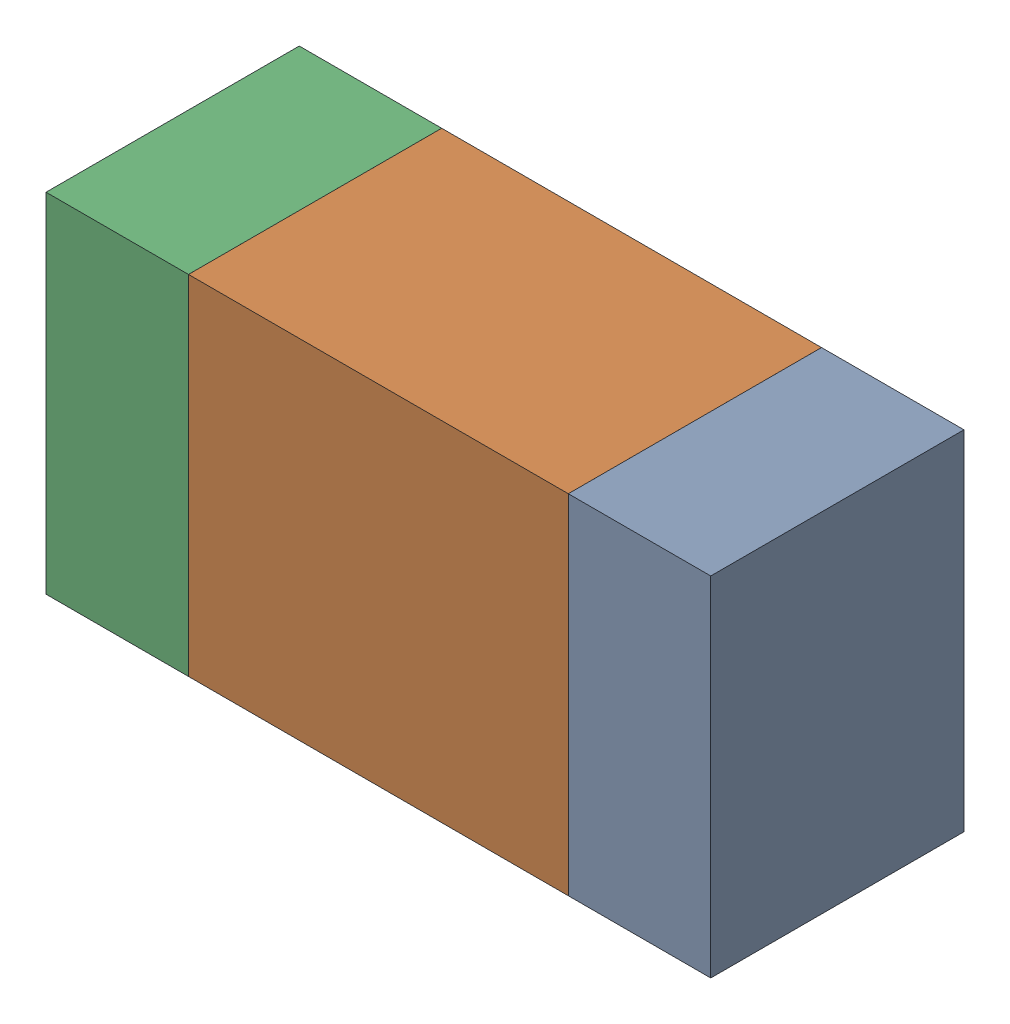
SolidWorks assembly R304_1PCB, configuration Default. Lengths in mm.
Overall size (1.05 0.55 0.4).
6 component instances, 2 part files, 0 mates.
Components (placement in the parent):
- 854785432-1: 854785432 [Default] at (145.3124 103.7001 0) size (0.22 0.55 0.4)
  - Extruded-1: Extruded [Default] at origin size (0.22 0.55 0.4)
- 854785568-1: 854785568 [Default] at (144.8999 103.7001 0) size (0.6 0.55 0.4)
  - Extruded_2-1: Extruded_2 [Default] at origin size (0.6 0.55 0.4)
- 854785432-2: 854785432 [Default] at (144.4874 103.7001 0) size (0.22 0.55 0.4)
  - Extruded-1: Extruded [Default] at origin size (0.22 0.55 0.4)
